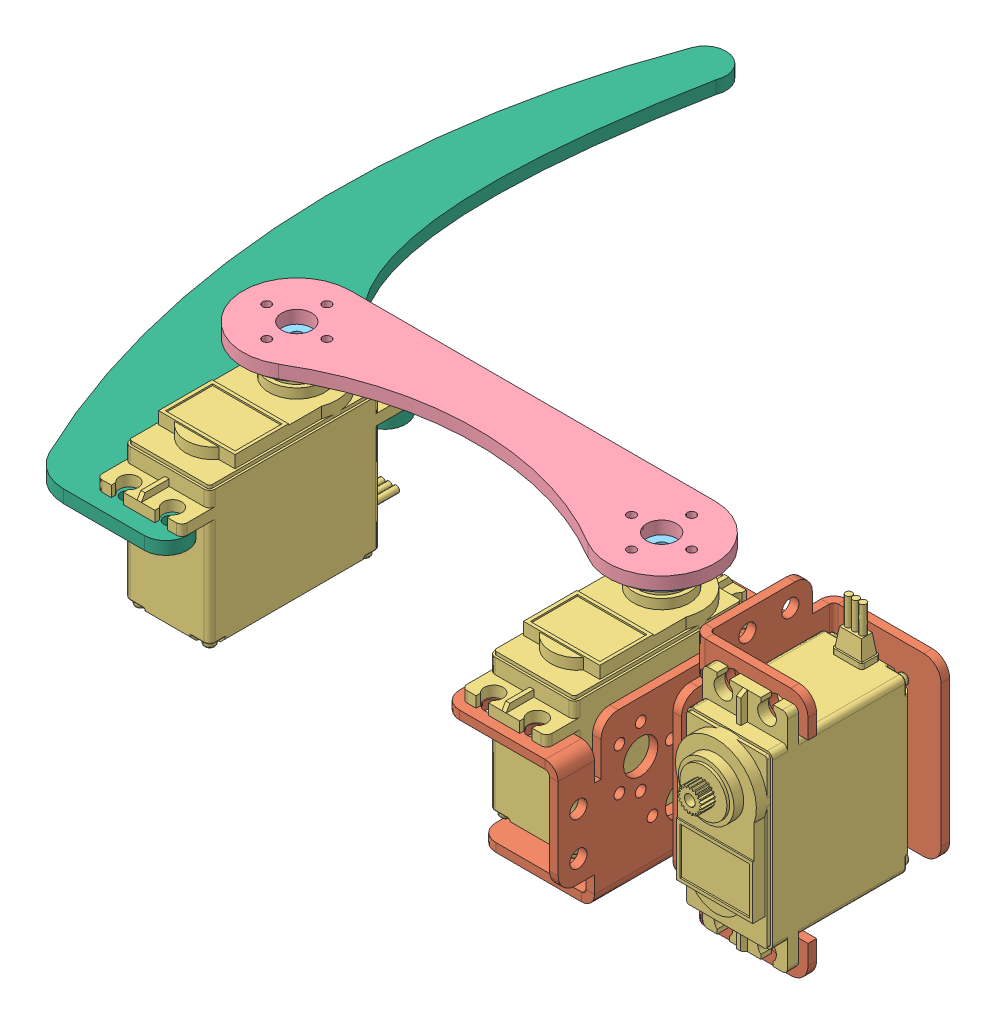
SolidWorks assembly left_leg, configuration Default. Lengths in mm.
Overall size (169.29 66.67 165.5).
10 component instances, 6 part files, 27 mates.
Components (placement in the parent):
- bearing-1: bearing [Default] at (0 0 -48.4217) x (0 -1 0) z (0 0 -1) size (9.5 9.5 4)
- coxa-1: coxa [Défaut] at (-14.87 -10 -48.4217) x (0 -1 0) z (0 0 1) size (58 27 37.5)
- servo-1: servo [Default] at (9.906 -10.287 -21.3907) x (-1 0 0) z (0 1 0) size (19.81 42.14 58.23)
- coxa-2: coxa [Défaut] at (-14.87 -25.75 -13.1717) x (0 0 -1) z (0 1 0) size (58 27 37.5)
- servo-2: servo [Default] at (-19.834 1.281 -12.8847) x (-1 0 0) z (0 0 -1) size (19.81 42.14 58.23)
- femur-1: femur [Default] at (-72.24 24.6717 -23.1717) x (-1 0 0) z (0 1 0) size (110 25 3)
- horn-1: horn [Default] at (-114.74 24.6717 -23.1717) x (-1 0 0) z (0 -1 0) size (20 20 4.5)
- horn-2: horn [Default] at (-29.74 24.6717 -23.1717) x (-1 0 0) z (0 -1 0) size (20 20 4.5)
- servo-3: servo [Default] at (-104.834 1.281 -12.8847) x (-1 0 0) z (0 0 -1) size (19.81 42.14 58.23)
- tibia-1: tibia [Default] at (-114.74 4.25 -23.1717) x (0 0 -1) z (0 1 0) size (165.5 56.86 3.1)
Mates (geometry in assembly coordinates):
- Concentric1: concentric anti-aligned: cylinder of bearing-1 through (0 0 -48.4217) axis (0 0 -1) radius 1; cylinder of coxa-1 through (0 0 -46.4217) axis (0 0 1) radius 1.25
- Coincident2: coincident anti-aligned: plane of bearing-1 through (0 0 -48.4217) normal (0 0 1); plane of coxa-1 through (12.13 -30.5 -48.4217) normal (0 0 -1)
- Concentric2: concentric aligned: cylinder of coxa-1 through (0 0 -46.4217) axis (0 0 1) radius 1.25; cylinder of servo-1 through (0 0 -9.6666) axis (0 0 1) radius 1.27
- Coincident3: coincident anti-aligned: plane of coxa-1 through (-14.87 -10 -15.4217) normal (0 0 1); plane of servo-1 through (-9.906 -10.287 -15.4217) normal (0 0 -1)
- Parallel1: parallel anti-aligned: plane of coxa-1 through (-12.87 -30.5 -48.4217) normal (1 0 0); plane of servo-1 through (-9.906 -10.287 -21.3907) normal (-1 0 0)
- Concentric3: concentric anti-aligned: cylinder of coxa-1 through (-12.87 -0.25 -22.9217) axis (1 0 0) radius 4; cylinder of coxa-2 through (-16.87 -0.25 -22.9217) axis (-1 0 0) radius 4
- Concentric4: concentric anti-aligned: cylinder of coxa-1 through (-12.87 -0.25 -15.9217) axis (1 0 0) radius 1.25; cylinder of coxa-2 through (-16.87 -0.25 -15.9217) axis (-1 0 0) radius 1.25
- Coincident5: coincident anti-aligned: plane of coxa-1 through (-14.87 -30.5 -48.4217) normal (-1 0 0); plane of coxa-2 through (-14.87 -25.75 -33.6717) normal (1 0 0)
- Concentric5: concentric aligned: cylinder of coxa-2 through (-29.74 -23.75 -23.1717) axis (0 1 0) radius 1.25; cylinder of servo-2 through (-29.74 13.0051 -23.1717) axis (0 1 0) radius 1.27
- Coincident6: coincident anti-aligned: plane of coxa-2 through (-14.87 7.25 -13.1717) normal (0 1 0); plane of servo-2 through (-39.646 7.25 -12.8847) normal (0 -1 0)
- Parallel2: parallel anti-aligned: plane of coxa-2 through (-16.87 -25.75 -33.6717) normal (-1 0 0); plane of servo-2 through (-19.834 1.281 -12.8847) normal (1 0 0)
- Concentric6: concentric anti-aligned: cylinder of femur-1 through (-114.74 27.6717 -23.1717) axis (0 -1 0) radius 3.5; cylinder of horn-1 through (-114.74 22.6717 -23.1717) axis (0 1 0) radius 1.5
- Concentric7: concentric anti-aligned: cylinder of femur-1 through (-121.74 27.6717 -23.1717) axis (0 -1 0) radius 1; cylinder of horn-1 through (-121.74 22.6717 -23.1717) axis (0 1 0) radius 1
- Coincident7: coincident anti-aligned: plane of femur-1 through (-29.74 24.6717 -23.1717) normal (0 -1 0); plane of horn-1 through (-114.74 24.6717 -23.1717) normal (0 1 0)
- Concentric8: concentric anti-aligned: cylinder of femur-1 through (-29.74 27.6717 -23.1717) axis (0 -1 0) radius 3.5; cylinder of horn-2 through (-29.74 22.6717 -23.1717) axis (0 1 0) radius 1.5
- Concentric9: concentric anti-aligned: cylinder of femur-1 through (-22.74 27.6717 -23.1717) axis (0 -1 0) radius 1; cylinder of horn-2 through (-22.74 22.6717 -23.1717) axis (0 1 0) radius 1
- Coincident8: coincident anti-aligned: plane of femur-1 through (-29.74 24.6717 -23.1717) normal (0 -1 0); plane of horn-2 through (-29.74 24.6717 -23.1717) normal (0 1 0)
- Concentric10: concentric aligned: cylinder of servo-2 through (-29.74 13.0051 -23.1717) axis (0 1 0) radius 1.27; cylinder of horn-2 through (-29.74 22.6717 -23.1717) axis (0 1 0) radius 1.5
- Coincident9: coincident anti-aligned: plane of servo-2 through (-39.646 22.6717 -12.8847) normal (0 1 0); plane of horn-2 through (-29.74 22.6717 -23.1717) normal (0 -1 0)
- Concentric11: concentric aligned: cylinder of horn-1 through (-114.74 22.6717 -23.1717) axis (0 1 0) radius 1.5; cylinder of servo-3 through (-114.74 13.0051 -23.1717) axis (0 1 0) radius 1.27
- Coincident10: coincident anti-aligned: plane of horn-1 through (-114.74 22.6717 -23.1717) normal (0 -1 0); plane of servo-3 through (-124.646 22.6717 -12.8847) normal (0 1 0)
- Coincident11: coincident anti-aligned: plane of servo-3 through (-124.646 7.25 -12.8847) normal (0 -1 0); plane of tibia-1 through (42.8373 7.25 -74.6842) normal (0 1 0)
- Parallel3: parallel anti-aligned: plane of servo-3 through (-124.646 1.281 -12.8847) normal (-1 0 0); plane of tibia-1 through (-126.74 7.25 7.3283) normal (1 0 0)
- Coincident13: coincident anti-aligned: line of servo-3 through (-114.74 16.5972 -23.1717) axis (0 1 0); line of tibia-1 through (-114.74 4.25 -23.1717) axis (0 -1 0)
- Coincident24: coordinate: point of servo-1; point of assembly
- Coincident25: coordinate: point of horn-1; point of servo-3
- Coincident27: coordinate: point of servo-2; point of horn-2
